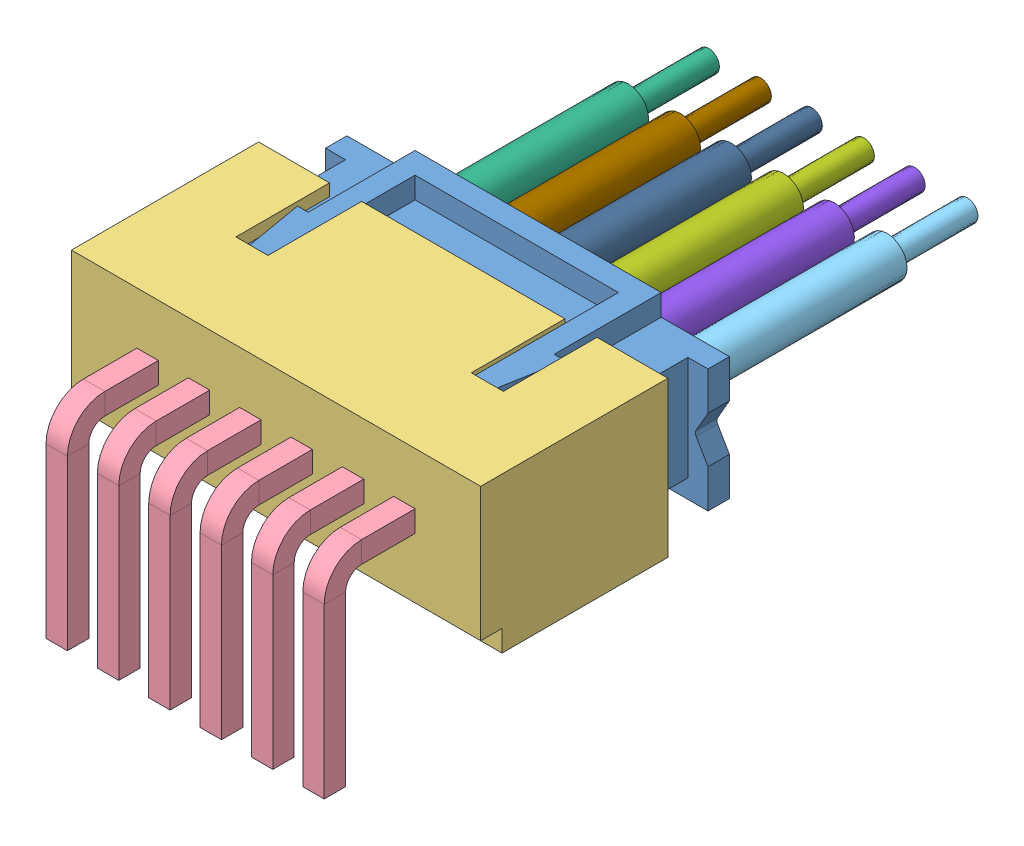
SolidWorks assembly Assem3, configuration Default. Lengths in mm.
Overall size (15.3 9.85 24.41).
20 component instances, 10 part files, 40 mates.
Components (placement in the parent):
- JST - XH MALE 6pin-1: JST - XH MALE 6pin [Default] at (6.1953 9.4344 9.1843) size (14.3 5.4 8.4)
- Part1-1: Part1 [Default] at (11.0353 9.8844 15.4843) x (1 0 0) z (0 1 0) size (1.8 6 3.23)
- Part1-2: Part1 [Default] at (9.0753 9.8844 15.4843) x (1 0 0) z (0 1 0) size (1.8 6 3.23)
- Part1-3: Part1 [Default] at (5.2353 9.8844 15.4843) x (1 0 0) z (0 1 0) size (1.8 6 3.23)
- Part1-4: Part1 [Default] at (7.1553 9.8844 15.4843) x (1 0 0) z (0 1 0) size (1.8 6 3.23)
- Part1-5: Part1 [Default] at (3.3153 9.8844 15.4843) x (1 0 0) z (0 1 0) size (1.8 6 3.23)
- Part1-6: Part1 [Default] at (1.3553 9.8844 15.4843) x (1 0 0) z (0 1 0) size (1.8 6 3.23)
- Part 1-2: Part 1 [Default] at (6.1953 9.6344 11.1843) x (-1 0 0) z (0 1 0) size (15.3 7 5.8)
- Part3-1: Part3 [Default] at (3.3153 10.1844 21.1843) x (0 0 1) z (-1 0 0) size (9.7 7.9 0.8)
- Part3-2: Part3 [Default] at (5.2353 10.1844 21.1843) x (0 0 1) z (-1 0 0) size (9.7 7.9 0.8)
- Part3-3: Part3 [Default] at (7.1553 10.1844 21.1843) x (0 0 1) z (-1 0 0) size (9.7 7.9 0.8)
- Part3-4: Part3 [Default] at (10.9953 10.1844 21.1843) x (0 0 1) z (-1 0 0) size (9.7 7.9 0.8)
- Part3-5: Part3 [Default] at (9.0753 10.1844 21.1843) x (0 0 1) z (-1 0 0) size (9.7 7.9 0.8)
- Part3-6: Part3 [Default] at (1.3953 10.1844 21.1843) x (0 0 1) z (-1 0 0) size (9.7 7.9 0.8)
- Part4-1: Part4 [Default] at (11.038 9.5733 0.1829) size (1.5 1.5 16)
- Part5-1: Part5 [Default] at (1.3683 9.573 0.1793) size (1.5 1.5 16)
- Part7-1: Part7 [Default] at (7.1674 9.5835 0.1857) size (1.5 1.5 16)
- Part8-1: Part8 [Default] at (9.077 9.5881 0.1932) size (1.5 1.5 16)
- Part9-1: Part9 [Default] at (3.3213 9.5991 0.1901) size (1.5 1.5 16)
- Part6-1: Part6 [Default] at (5.2194 9.5846 0.1826) size (1.5 1.5 16)
Mates (geometry in assembly coordinates):
- Width1: width anti-aligned: plane of Part1-1 through (10.1353 8.7344 13.3843) normal (-1 0 0); plane of Part1-1 through (11.9353 8.7344 13.3843) normal (1 0 0); plane of JST - XH MALE 6pin-1 through (10.0753 11.2844 15.8843) normal (1 0 0); plane of JST - XH MALE 6pin-1 through (11.9953 11.2844 15.8843) normal (-1 0 0)
- Width2: width anti-aligned: plane of Part1-1 through (10.1353 11.0344 13.3843) normal (0 1 0); plane of Part1-1 through (10.1353 8.7344 13.3843) normal (0 -1 0); plane of JST - XH MALE 6pin-1 through (10.0753 11.2844 15.8843) normal (0 -1 0); plane of JST - XH MALE 6pin-1 through (11.3953 8.4844 15.8843) normal (0 1 0)
- Width3: width anti-aligned: plane of Part1-2 through (8.1753 8.7344 13.3843) normal (-1 0 0); plane of Part1-2 through (9.9753 8.7344 13.3843) normal (1 0 0); plane of JST - XH MALE 6pin-1 through (8.1553 11.2844 15.8843) normal (1 0 0); plane of JST - XH MALE 6pin-1 through (9.9953 11.2844 15.8843) normal (-1 0 0)
- Width4: width anti-aligned: plane of Part1-2 through (8.1753 11.0344 13.3843) normal (0 1 0); plane of Part1-2 through (8.1753 8.7344 13.3843) normal (0 -1 0); plane of JST - XH MALE 6pin-1 through (8.1553 11.2844 15.8843) normal (0 -1 0); plane of JST - XH MALE 6pin-1 through (9.4753 8.4844 15.8843) normal (0 1 0)
- Width5: width anti-aligned: plane of Part1-3 through (6.1353 8.7344 13.3843) normal (1 0 0); plane of Part1-3 through (4.3353 8.7344 13.3843) normal (-1 0 0); plane of JST - XH MALE 6pin-1 through (6.1553 11.2844 15.8843) normal (-1 0 0); plane of JST - XH MALE 6pin-1 through (4.3153 11.2844 15.8843) normal (1 0 0)
- Width6: width anti-aligned: plane of Part1-3 through (4.3353 11.0344 13.3843) normal (0 1 0); plane of Part1-3 through (4.3353 8.7344 13.3843) normal (0 -1 0); plane of JST - XH MALE 6pin-1 through (4.3153 11.2844 15.8843) normal (0 -1 0); plane of JST - XH MALE 6pin-1 through (4.3153 8.4844 15.8843) normal (0 1 0)
- Width7: width anti-aligned: plane of Part1-4 through (6.2553 11.0344 13.3843) normal (0 1 0); plane of Part1-4 through (6.2553 8.7344 13.3843) normal (0 -1 0); plane of JST - XH MALE 6pin-1 through (6.2353 11.2844 15.8843) normal (0 -1 0); plane of JST - XH MALE 6pin-1 through (6.2353 8.4844 15.8843) normal (0 1 0)
- Width8: width aligned: plane of Part1-4 through (8.0553 8.7344 13.3843) normal (1 0 0); plane of Part1-4 through (6.2553 8.7344 13.3843) normal (-1 0 0); plane of JST - XH MALE 6pin-1 through (6.2353 11.2844 15.8843) normal (1 0 0); plane of JST - XH MALE 6pin-1 through (8.0753 11.2844 15.8843) normal (-1 0 0)
- Width9: width anti-aligned: plane of Part1-5 through (2.4153 8.7344 13.3843) normal (-1 0 0); plane of Part1-5 through (4.2153 8.7344 13.3843) normal (1 0 0); plane of JST - XH MALE 6pin-1 through (2.3953 11.2844 15.8843) normal (1 0 0); plane of JST - XH MALE 6pin-1 through (4.2353 11.2844 15.8843) normal (-1 0 0)
- Width10: width anti-aligned: plane of Part1-5 through (2.4153 11.0344 13.3843) normal (0 1 0); plane of Part1-5 through (2.4153 8.7344 13.3843) normal (0 -1 0); plane of JST - XH MALE 6pin-1 through (2.3953 11.2844 15.8843) normal (0 -1 0); plane of JST - XH MALE 6pin-1 through (2.3953 8.4844 15.8843) normal (0 1 0)
- Width11: width anti-aligned: plane of Part1-6 through (0.4553 11.0344 13.3843) normal (0 1 0); plane of Part1-6 through (0.4553 8.7344 13.3843) normal (0 -1 0); plane of JST - XH MALE 6pin-1 through (0.3953 11.2844 15.8843) normal (0 -1 0); plane of JST - XH MALE 6pin-1 through (0.3953 8.4844 15.8843) normal (0 1 0)
- Width12: width aligned: plane of Part1-6 through (2.2553 8.7344 13.3843) normal (1 0 0); plane of Part1-6 through (0.4553 8.7344 13.3843) normal (-1 0 0); plane of JST - XH MALE 6pin-1 through (0.3953 11.2844 15.8843) normal (1 0 0); plane of JST - XH MALE 6pin-1 through (2.3153 11.2844 15.8843) normal (-1 0 0)
- Distance1: distance = 0.4 mm anti-aligned: plane of Part1-1 through (11.0353 9.8844 15.4843) normal (0 0 1); plane of JST - XH MALE 6pin-1 through (6.1953 9.4344 15.8843) normal (0 0 -1)
- Distance2: distance = 0.4 mm anti-aligned: plane of Part1-2 through (9.0753 9.8844 15.4843) normal (0 0 1); plane of JST - XH MALE 6pin-1 through (6.1953 9.4344 15.8843) normal (0 0 -1)
- Distance3: distance = 0.4 mm anti-aligned: plane of JST - XH MALE 6pin-1 through (6.1953 9.4344 15.8843) normal (0 0 -1); plane of Part1-4 through (7.1553 9.8844 15.4843) normal (0 0 1)
- Distance4: distance = 0.4 mm anti-aligned: plane of Part1-3 through (5.2353 9.8844 15.4843) normal (0 0 1); plane of JST - XH MALE 6pin-1 through (6.1953 9.4344 15.8843) normal (0 0 -1)
- Distance5: distance = 0.4 mm anti-aligned: plane of Part1-5 through (3.3153 9.8844 15.4843) normal (0 0 1); plane of JST - XH MALE 6pin-1 through (6.1953 9.4344 15.8843) normal (0 0 -1)
- Distance6: distance = 0.4 mm anti-aligned: plane of Part1-6 through (1.3553 9.8844 15.4843) normal (0 0 1); plane of JST - XH MALE 6pin-1 through (6.1953 9.4344 15.8843) normal (0 0 -1)
- Width13: width anti-aligned: plane of ? through (-0.3047 19.037 23.0922) normal (1 0 0); plane of ? through (12.6953 19.037 23.0922) normal (-1 0 0); plane of JST - XH MALE 6pin-1 through (-0.2047 7.2844 16.1843) normal (-1 0 0); plane of JST - XH MALE 6pin-1 through (12.5953 7.2844 16.1843) normal (1 0 0)
- Width15: width anti-aligned: plane of Part 1-2 through (12.6953 12.0844 16.1843) normal (0 -1 0); plane of Part 1-2 through (12.6953 7.1844 16.1843) normal (0 1 0); plane of JST - XH MALE 6pin-1 through (-0.2047 11.5844 16.1843) normal (0 1 0); plane of JST - XH MALE 6pin-1 through (6.1953 7.6844 9.1843) normal (0 -1 0)
- Width16: width anti-aligned: plane of Part 1-2 through (-0.3047 7.1844 16.1843) normal (1 0 0); plane of Part 1-2 through (12.6953 7.1844 16.1843) normal (-1 0 0); plane of JST - XH MALE 6pin-1 through (-0.2047 7.2844 16.1843) normal (-1 0 0); plane of JST - XH MALE 6pin-1 through (12.5953 7.2844 16.1843) normal (1 0 0)
- LimitDistance1: limit distance = 0 mm anti-aligned: plane of Part 1-2 through (6.1953 9.6344 16.1843) normal (0 0 -1); plane of JST - XH MALE 6pin-1 through (6.1953 9.4344 16.1843) normal (0 0 1)
- Coincident1: coincident aligned: plane of Part3-1 through (3.7153 10.5844 20.1843) normal (0 1 0); plane of Part3-3 through (7.5553 10.5844 20.1843) normal (0 1 0)
- Coincident2: coincident aligned: plane of Part3-3 through (7.5553 10.5844 20.1843) normal (0 1 0); plane of Part3-6 through (1.7953 10.5844 20.1843) normal (0 1 0)
- Coincident3: coincident aligned: plane of Part3-2 through (5.6353 10.5844 20.1843) normal (0 1 0); plane of Part3-6 through (1.7953 10.5844 20.1843) normal (0 1 0)
- Coincident4: coincident aligned: plane of Part3-2 through (5.6353 10.5844 20.1843) normal (0 1 0); plane of Part3-5 through (9.4753 10.5844 20.1843) normal (0 1 0)
- Coincident5: coincident aligned: plane of Part3-4 through (11.3953 10.5844 20.1843) normal (0 1 0); plane of Part3-5 through (9.4753 10.5844 20.1843) normal (0 1 0)
- Coincident6: coincident anti-aligned: plane of Part 1-2 through (0.9953 10.5844 8.1843) normal (0 -1 0); plane of Part3-1 through (3.7153 10.5844 20.1843) normal (0 1 0)
- Coincident7: coincident aligned: plane of Part3-1 through (3.7153 9.1844 21.5843) normal (0 0 1); plane of Part3-3 through (7.5553 9.1844 21.5843) normal (0 0 1)
- Coincident8: coincident aligned: plane of Part3-3 through (7.5553 9.1844 21.5843) normal (0 0 1); plane of Part3-6 through (1.7953 9.1844 21.5843) normal (0 0 1)
- Coincident9: coincident aligned: plane of Part3-5 through (9.4753 9.1844 21.5843) normal (0 0 1); plane of Part3-6 through (1.7953 9.1844 21.5843) normal (0 0 1)
- Coincident10: coincident aligned: plane of Part3-4 through (11.3953 9.1844 21.5843) normal (0 0 1); plane of Part3-5 through (9.4753 9.1844 21.5843) normal (0 0 1)
- Coincident11: coincident aligned: plane of Part3-1 through (3.7153 9.1844 21.5843) normal (0 0 1); plane of Part3-2 through (5.6353 9.1844 21.5843) normal (0 0 1)
- Coincident12: coincident anti-aligned: plane of Part 1-2 through (0.9953 10.5844 8.1843) normal (1 0 0); plane of Part3-6 through (0.9953 10.5844 20.1843) normal (-1 0 0)
- Coincident13: coincident anti-aligned: plane of Part 1-2 through (2.9153 10.5844 8.1843) normal (1 0 0); plane of Part3-1 through (2.9153 10.5844 20.1843) normal (-1 0 0)
- Coincident14: coincident anti-aligned: plane of Part 1-2 through (4.8353 10.5844 8.1843) normal (1 0 0); plane of Part3-2 through (4.8353 10.5844 20.1843) normal (-1 0 0)
- Coincident15: coincident anti-aligned: plane of Part 1-2 through (6.7553 10.5844 8.1843) normal (1 0 0); plane of Part3-3 through (6.7553 10.5844 20.1843) normal (-1 0 0)
- Coincident16: coincident anti-aligned: plane of Part 1-2 through (8.6753 10.5844 8.1843) normal (1 0 0); plane of Part3-5 through (8.6753 10.5844 20.1843) normal (-1 0 0)
- Coincident17: coincident anti-aligned: plane of Part 1-2 through (10.5953 10.5844 8.1843) normal (1 0 0); plane of Part3-4 through (10.5953 10.5844 20.1843) normal (-1 0 0)
- Distance8: distance = 0.7 mm aligned: plane of Part3-4 through (10.9953 10.1844 11.8843) normal (0 0 -1); plane of Part 1-2 through (6.1953 9.6344 11.1843) normal (0 0 -1)
